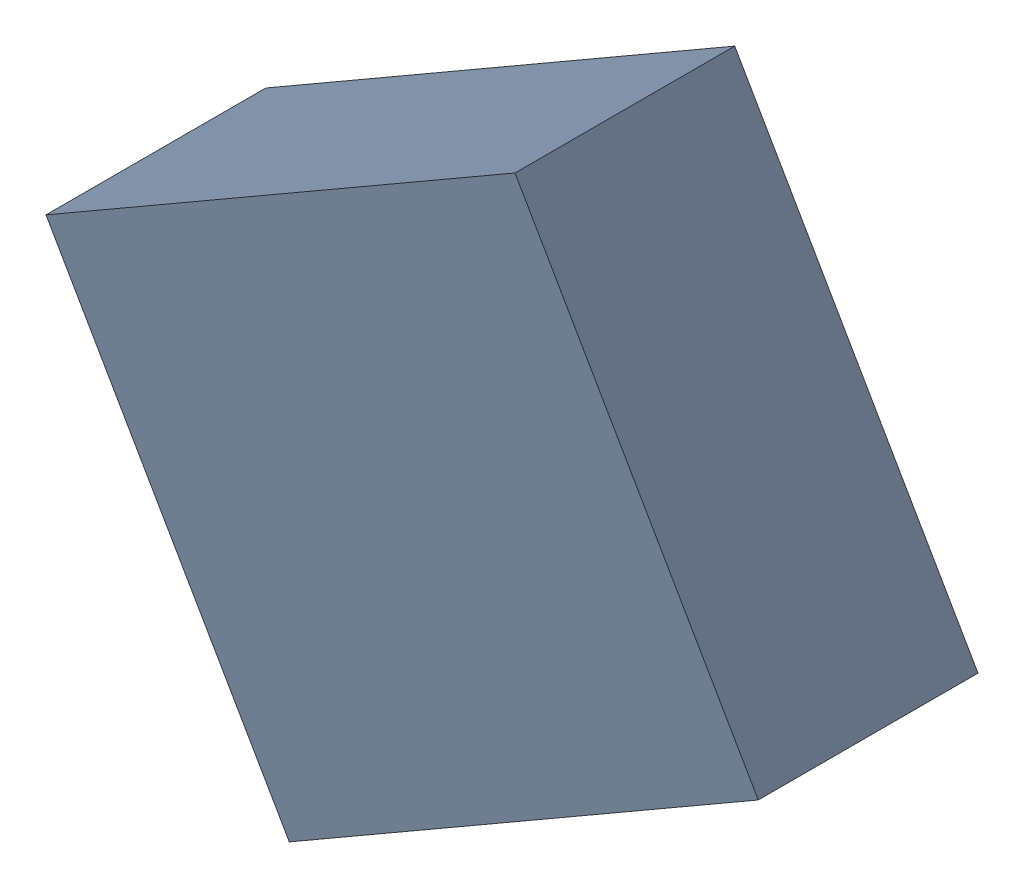
SolidWorks assembly F1_TDA5, configuration Standard. Lengths in mm.
Overall size (4.54 4.41 1.4).
2 component instances, 1 part files, 0 mates.
Components (placement in the parent):
- 885545232-1: 885545232 [Standard] at (-46.5044 -33.8279 0) size (4.54 4.41 1.4)
  - Extruded_4-1: Extruded_4 [Standard] at origin size (4.54 4.41 1.4)
